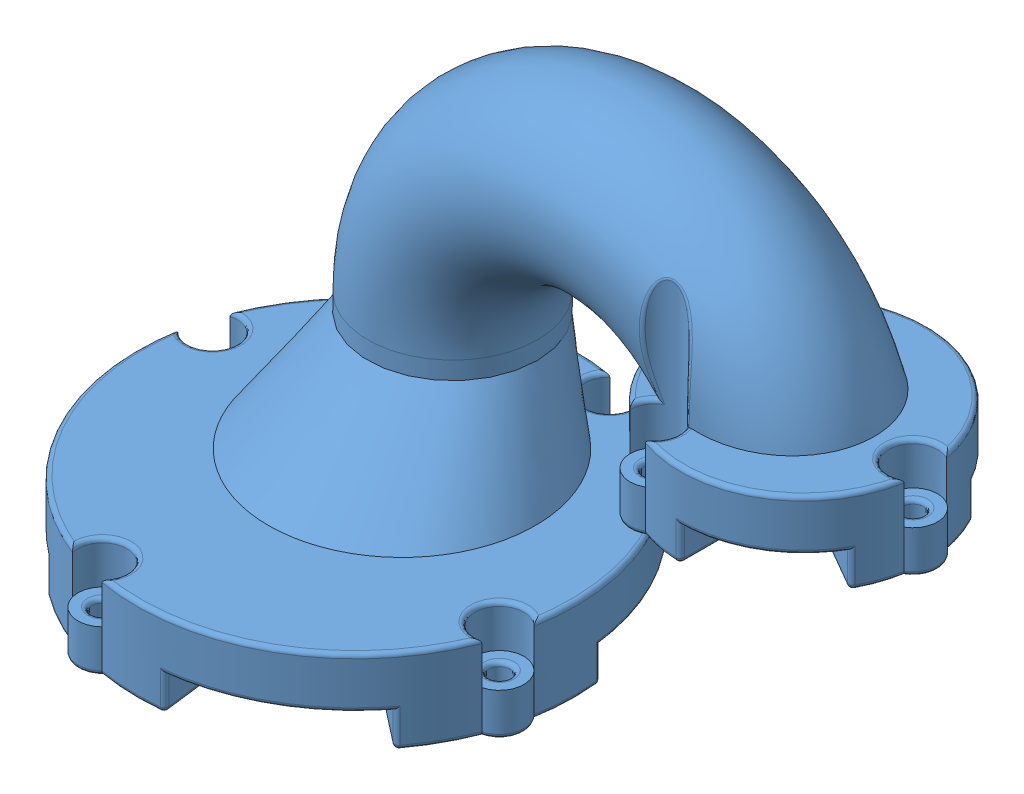
SolidWorks assembly U Tube Reference Assembly, configuration Default. Lengths in mm.
Overall size (83.46 53.84 52.58).
2 component instances, 2 part files, 5 mates.
Components (placement in the parent):
- Water Tunnel-1: Water Tunnel [Default] at origin size (93.6 95.13 58.74) (hidden)
- U Tube-1: U Tube [Default] at (0 9 0) x (1 0 0) z (0 1 0) size (83.46 52.58 53.84)
Mates (geometry in assembly coordinates):
- Coincident1: coordinate: point of Water Tunnel-1
- InPlace1: in place: plane of Water Tunnel-1 through (0 9 0) normal (0 1 0); plane of U Tube-1 through (0 9 0) normal (0 1 0); moOrthogonalPlaneRef_w of Water Tunnel-1 through (0 9 0) normal (0 1 0); plane of U Tube-1 through (0 9 0) normal (0 0 -1); plane of Water Tunnel-1 through (0 9 0) normal (0 1 0); plane of U Tube-1 through (0 9 0) normal (1 0 0); plane of Water Tunnel-1 through (0 9 0) normal (0 1 0); unknown of U Tube-1
- Coincident2: coincident aligned: plane of Water Tunnel-1; plane of U Tube-1
- Coincident3: coincident aligned: moOrthogonalPlaneRef_w of Water Tunnel-1 through (0 9 0) normal (0 0 -1); plane of U Tube-1 through (0 9 0) normal (0 0 -1)
- Coincident4: coincident anti-aligned: moOrthogonalPlaneRef_w of Water Tunnel-1 through (0 9 0) normal (-1 0 0); plane of U Tube-1 through (0 9 0) normal (1 0 0)
